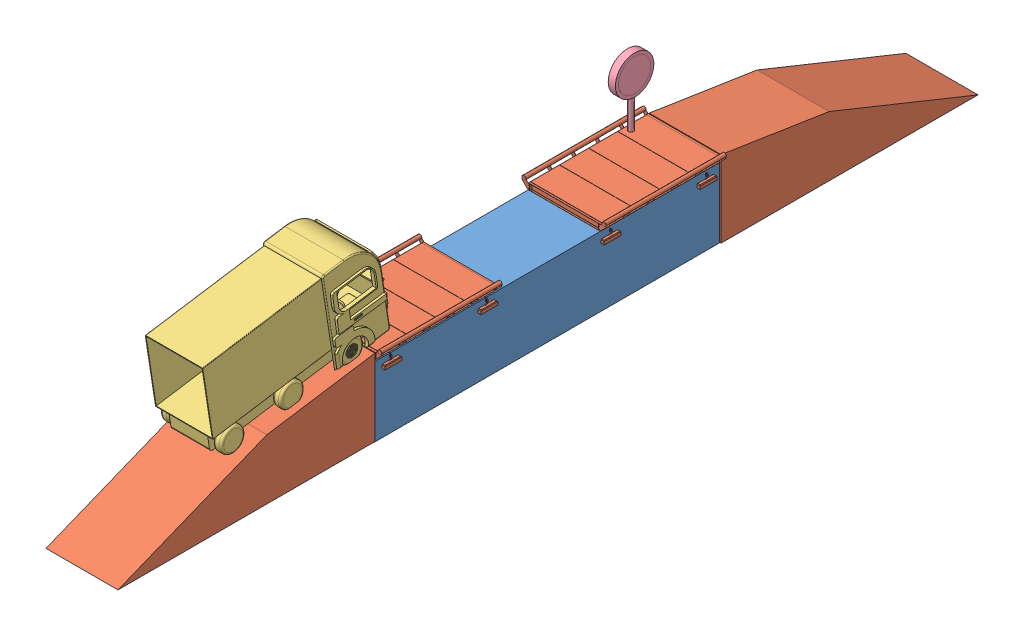
SolidWorks assembly weight bridge, configuration Default. Lengths in mm.
Overall size (3504.97 7214.03 35832.36).
5 component instances, 4 part files, 4 mates.
Components (placement in the parent):
- fluid balance-1: fluid balance [Default] at (13200 -1244.1363 -552.9495) size (3000 2900 14400)
- Weighing bridge mod-1: Weighing bridge mod [Default] at (11700 158.5499 1174.6138) size (3504.97 3378.52 15753.88)
- truck part 1-1: truck part 1 [Default] at (14452.5735 690.6196 5302.4981) x (0 -0.152405 0.988318) z (-1 0 0) size (7410 3990.37 2695)
- Weighing bridge mod-2: Weighing bridge mod [Default] at (14700 105.8637 -3193.9762) x (-1 0 0) z (0 0 -1) size (3504.97 3378.52 15753.88)
- weight guage-1: weight guage [Default] at (11954.7512 183.3051 -7214.0467) x (0 0 -1) z (1 0 0) size (1600 3055.41 300)
Mates (geometry in assembly coordinates):
- Concentric1: concentric anti-aligned: cylinder of fluid balance-1 through (13200 414.7121 3602.2905) axis (0 -1 0) radius 400; cylinder of Weighing bridge mod-1 through (13200 -193.4501 3602.2905) axis (0 1 0) radius 300
- Parallel1: parallel anti-aligned: line of Weighing bridge mod-1 through (14700 -283.881 10704.6138) axis (0 0.152405 -0.988318); line of truck part 1-1 through (13942.8467 524.8036 5721.6365) axis (0 -0.152405 0.988318)
- Concentric3: concentric aligned: cylinder of fluid balance-1 through (13200 -1983.7506 -5621.653) axis (0 1 0) radius 400; cylinder of Weighing bridge mod-2 through (13200 -246.1363 -5621.653) axis (0 1 0) radius 300
- Coincident4: coincident anti-aligned: plane of fluid balance-1 through (14700 105.8637 6047.0505) normal (0 1 0); plane of Weighing bridge mod-2 through (14553.9 105.8637 -8193.9762) normal (0 -1 0)
